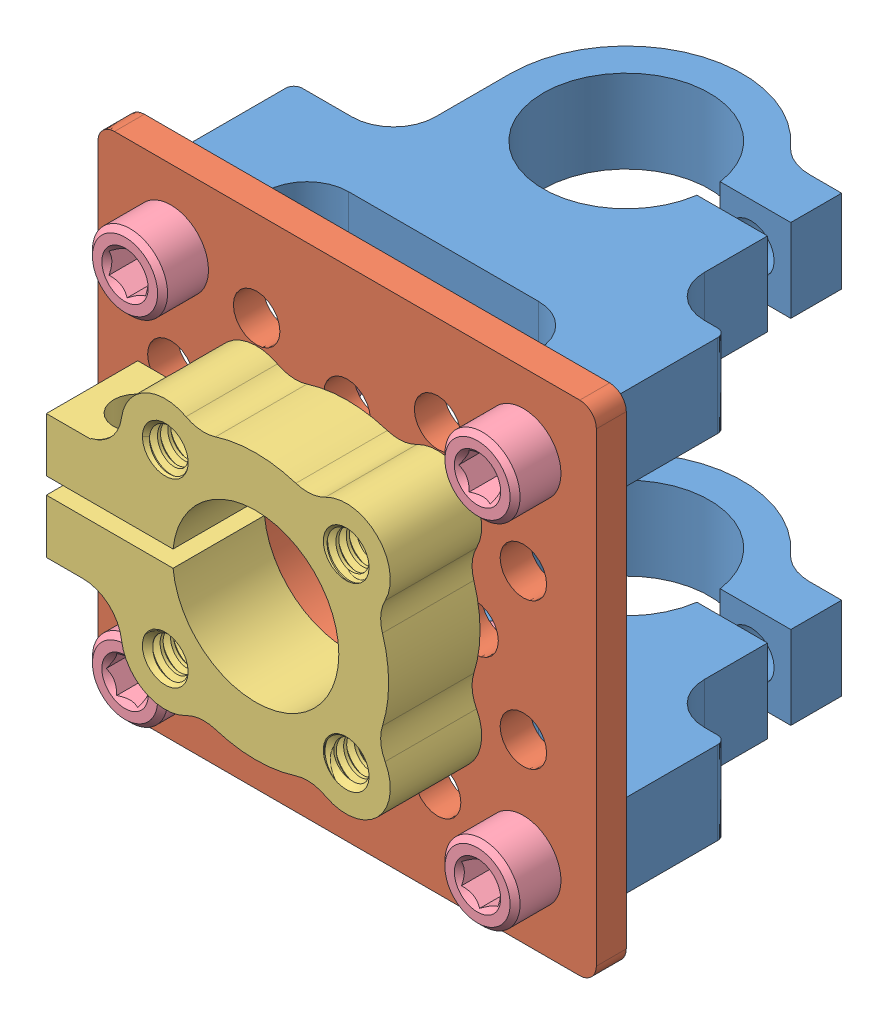
SolidWorks assembly Diff Pivot Swivel, configuration Default. Lengths in mm.
Overall size (38.1 38.1 37.32).
15 component instances, 4 part files, 13 mates.
Components (placement in the parent):
- 0.5 Bore Bottom Tapped Clamping Mount-1: 0.5 Bore Bottom Tapped Clamping Mount [Default] at (101.5047 -5.8505 -6.031) size (33.02 6.35 28.05)
  - 585546-1: 585546 [Default] at (-106.2884 25.7199 31.239) size (33.02 6.35 28.05)
- 0.5 Bore Bottom Tapped Clamping Mount-2: 0.5 Bore Bottom Tapped Clamping Mount [Default] at (101.5047 21.0903 -6.031) size (33.02 6.35 28.05)
  - 585546-1: 585546 [Default] at (-106.2884 25.7199 31.239) size (33.02 6.35 28.05)
- 1 Hole Pattern Bracket-1: 1 Hole Pattern Bracket [Default] at (-4.7838 36.5148 46.544) x (1 0 0) z (0 1 0) size (38.1 2.29 38.1)
- 0.5 Bore Side Tapped Clamping Hub-1: 0.5 Bore Side Tapped Clamping Hub [Default] at (-17.841 70.0403 34.8585) x (0 1 0) z (1 0 0) size (20.57 7.21 26.29)
  - 545600-1: 545600 [Default] at (-33.5255 9.1455 13.0572) size (20.57 7.21 26.29)
- 6-32_SHCS-2: 6-32_SHCS [6-32 SHCS X .250] at (8.6866 49.9852 40.194) size (5.74 5.74 9.86)
- 6-32_SHCS-4: 6-32_SHCS [6-32 SHCS X .250] at (2.131 29.6 50.608) x (0.923728 0.383049 0) z (0 0 -1) size (5.74 5.74 9.86)
- 6-32_SHCS-5: 6-32_SHCS [6-32 SHCS X .250] at (-11.6986 29.6 50.608) x (0.383049 -0.923728 0) z (0 0 -1) size (5.74 5.74 9.86)
- 6-32_SHCS-6: 6-32_SHCS [6-32 SHCS X .250] at (-11.6986 43.4296 50.608) x (-0.923728 -0.383049 0) z (0 0 -1) size (5.74 5.74 9.86)
- 6-32_SHCS-7: 6-32_SHCS [6-32 SHCS X .250] at (2.131 43.4296 50.608) x (-0.383049 0.923728 0) z (0 0 -1) size (5.74 5.74 9.86)
- 6-32_SHCS-8: 6-32_SHCS [6-32 SHCS X .250] at (8.6866 23.0444 40.194) x (0 -1 0) z (0 0 1) size (5.74 5.74 9.86)
- 6-32_SHCS-9: 6-32_SHCS [6-32 SHCS X .250] at (-18.2542 23.0444 40.194) x (-1 0 0) z (0 0 1) size (5.74 5.74 9.86)
- 6-32_SHCS-10: 6-32_SHCS [6-32 SHCS X .250] at (-18.2542 49.9852 40.194) x (0 1 0) z (0 0 1) size (5.74 5.74 9.86)
Mates (geometry in assembly coordinates):
- Coincident1: coincident anti-aligned: plane of 1 Hole Pattern Bracket-1 through (-4.7838 36.5148 44.258) normal (0 0 -1); plane of 0.5 Bore Bottom Tapped Clamping Mount-2/585546-1 through (-4.7838 53.1602 44.258) normal (0 0 1)
- Coincident2: coincident anti-aligned: plane of 1 Hole Pattern Bracket-1 through (-4.7838 36.5148 44.258) normal (0 0 -1); plane of 0.5 Bore Bottom Tapped Clamping Mount-1/585546-1 through (-4.7838 26.2194 44.258) normal (0 0 1)
- Concentric1: concentric anti-aligned: cylinder of 1 Hole Pattern Bracket-1 through (8.6866 49.9852 44.258) axis (0 0 -1) radius 1.778; cylinder of 0.5 Bore Bottom Tapped Clamping Mount-2/585546-1 through (8.6866 49.9852 44.258) axis (0 0 1) radius 1.3526
- Concentric2: concentric aligned: cylinder of 1 Hole Pattern Bracket-1 through (8.6866 49.9852 44.258) axis (0 0 -1) radius 1.778; circle of 6-32_SHCS-2
- Concentric3: concentric anti-aligned: cylinder of 6-32_SHCS-4 through (2.131 29.6 31.558) axis (0 0 1) radius 2.8702; cylinder of 1 Hole Pattern Bracket-1 through (2.131 29.6 44.258) axis (0 0 -1) radius 1.778
- Concentric5: concentric anti-aligned: cylinder of 0.5 Bore Bottom Tapped Clamping Mount-2/585546-1 through (-18.2542 49.9852 44.258) axis (0 0 1) radius 1.3526; cylinder of 1 Hole Pattern Bracket-1 through (-18.2542 49.9852 44.258) axis (0 0 -1) radius 1.778
- Concentric6: concentric anti-aligned: cylinder of 0.5 Bore Bottom Tapped Clamping Mount-1/585546-1 through (8.6866 23.0444 44.258) axis (0 0 1) radius 1.3526; cylinder of 1 Hole Pattern Bracket-1 through (8.6866 23.0444 44.258) axis (0 0 -1) radius 1.778
- Concentric7: concentric anti-aligned: cylinder of 0.5 Bore Bottom Tapped Clamping Mount-1/585546-1 through (-18.2542 23.0444 44.258) axis (0 0 1) radius 1.3526; cylinder of 1 Hole Pattern Bracket-1 through (-18.2542 23.0444 44.258) axis (0 0 -1) radius 1.778
- Concentric10: concentric anti-aligned: cylinder of 1 Hole Pattern Bracket-1 through (2.131 43.4296 44.258) axis (0 0 -1) radius 1.778; cylinder of 0.5 Bore Side Tapped Clamping Hub-1/545600-1 through (2.131 43.4296 53.529) axis (0 0 1) radius 1.3526
- Concentric11: concentric anti-aligned: cylinder of 1 Hole Pattern Bracket-1 through (-11.6986 43.4296 44.258) axis (0 0 -1) radius 1.778; cylinder of 0.5 Bore Side Tapped Clamping Hub-1/545600-1 through (-11.6986 43.4296 53.529) axis (0 0 1) radius 1.3526
- Coincident3: coincident anti-aligned: plane of 1 Hole Pattern Bracket-1 through (-4.7838 36.5148 46.544) normal (0 0 1); plane of 6-32_SHCS-2 through (8.6866 49.9852 46.544) normal (0 0 -1)
- Coincident4: coincident anti-aligned: plane of 1 Hole Pattern Bracket-1 through (-4.7838 36.5148 46.544) normal (0 0 1); plane of 0.5 Bore Side Tapped Clamping Hub-1/545600-1 through (-4.7838 36.5148 46.544) normal (0 0 -1)
- Coincident5: coincident anti-aligned: plane of 1 Hole Pattern Bracket-1 through (-4.7838 36.5148 44.258) normal (0 0 -1); plane of 6-32_SHCS-4 through (2.131 29.6 44.258) normal (0 0 1)
